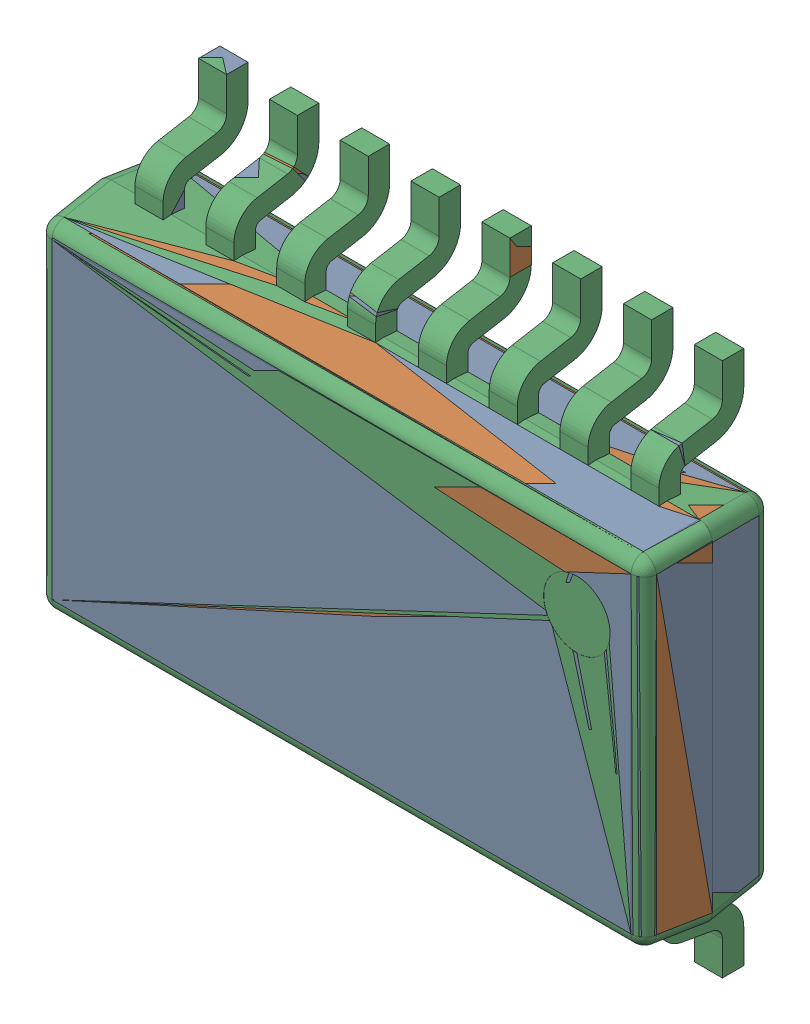
SolidWorks assembly U4, configuration Défaut. Lengths in mm.
Overall size (4.6 4 1.05).
3 component instances, 2 part files, 0 mates.
Components (placement in the parent):
- SSOP-16_L4.6-W2.6-P0.53-LS4.0-BL-1: SSOP-16_L4.6-W2.6-P0.53-LS4.0-BL [Défaut] at (50.742 -27.3 -1.6) x (-1 0 0) z (0 0 1) size (4.6 4 1.05)
- SSOP-16_L4.6-W2.6-P0.53-LS4.0-BL-2: SSOP-16_L4.6-W2.6-P0.53-LS4.0-BL [Défaut] at (50.742 -27.3 -1.6) x (-1 0 0) z (0 0 1) size (4.6 4 1.05)
- SSOP-16_L4.6-W2.6-P0.53-LS4.0-BL_827-1: SSOP-16_L4.6-W2.6-P0.53-LS4.0-BL_827 [Défaut] at (50.742 -27.3 -1.6) x (-1 0 0) z (0 0 1) size (4.6 4 1.05)
